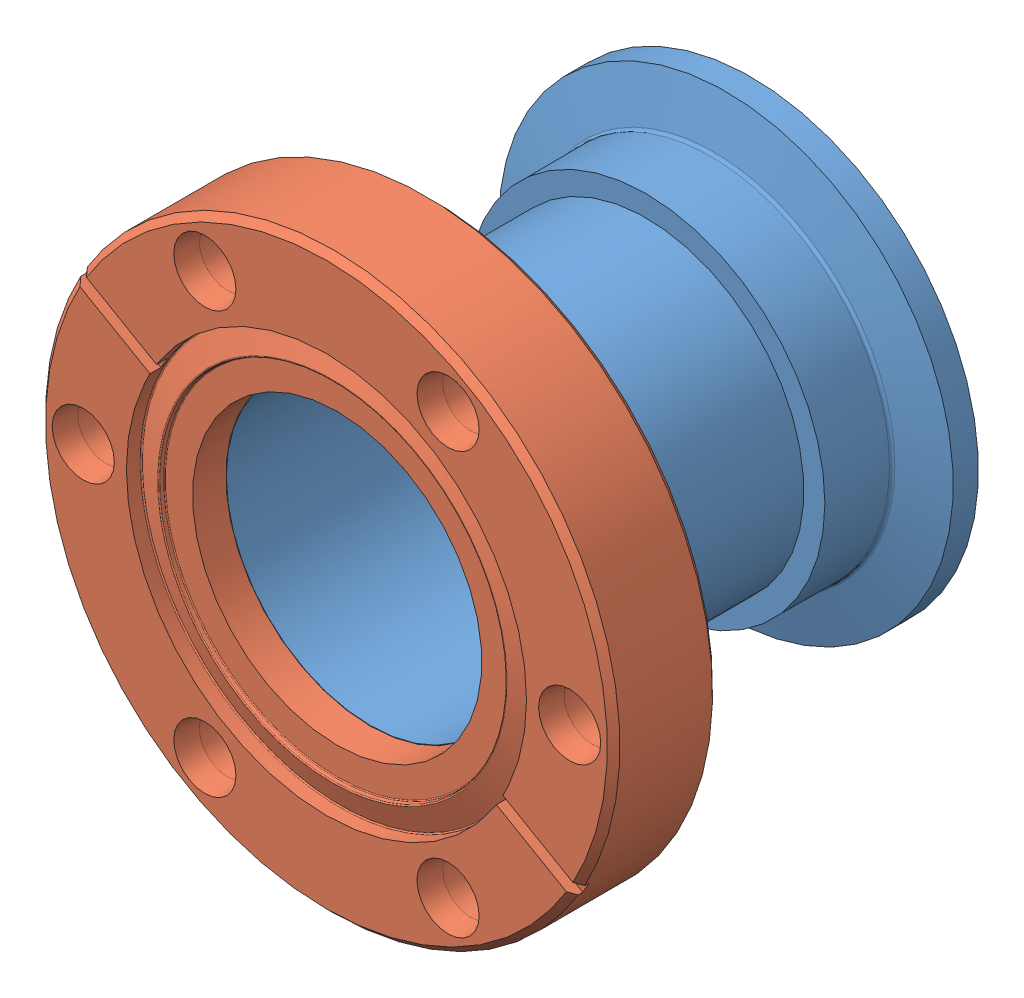
SolidWorks assembly 730003, configuration Default. Lengths in mm.
Overall size (69.34 69.34 51.28).
2 component instances, 2 part files, 3 mates.
Components (placement in the parent):
- 736003-REV.C-1: 736003-REV.C [Default] at (39.9075 26.2821 5.8498) size (54.86 54.86 45.97)
- 110014-REV.A-1: 110014-REV.A [Default] at (39.9075 26.2821 44.4324) x (0 -1 0) z (0 0 1) size (69.34 69.34 12.7)
Mates (geometry in assembly coordinates):
- Concentric2: concentric aligned: cylinder of 736003-REV.C-1 through (39.9075 26.2821 5.8498) axis (0 0 -1) radius 19.05; cylinder of 110014-REV.A-1 through (39.9075 26.2821 44.4324) axis (0 0 -1) radius 19.177
- Coincident1: coincident anti-aligned: plane of 736003-REV.C-1 through (57.3065 26.2821 51.8238) normal (0 0 1); plane of 110014-REV.A-1 through (39.9075 7.1051 51.8238) normal (0 0 -1)
- Parallel1: parallel aligned: plane of 110014-REV.A-1 through (39.9075 26.2821 44.4324) normal (1 0 0)
